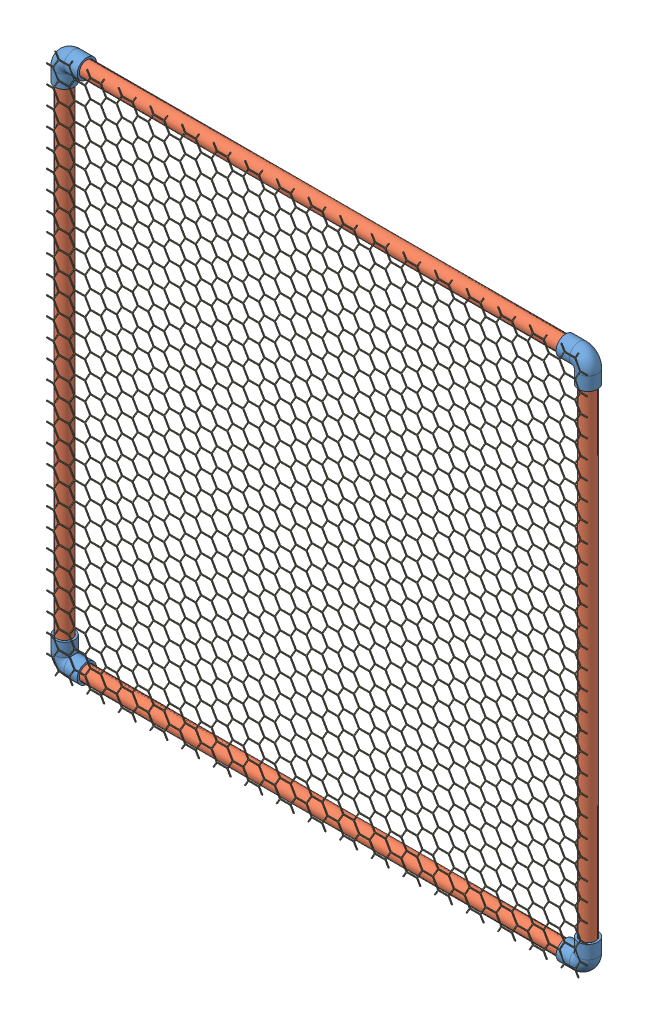
SolidWorks assembly LIFT BASKET, configuration Default. Lengths in mm.
Overall size (772.96 775.18 29.9).
9 component instances, 3 part files, 19 mates.
Components (placement in the parent):
- 1-2 PVC ELBOW-1: 1-2 PVC ELBOW [4880K21] at (72.2447 -84.4761 79.3271) size (45.53 45.53 27.56)
- 1-2 PVC ELBOW-2: 1-2 PVC ELBOW [4880K21] at (-673.1553 -84.4761 79.3271) x (0 -1 0) z (0 0 1) size (45.53 45.53 27.56)
- 1-2 PVC ELBOW-3: 1-2 PVC ELBOW [4880K21] at (-673.1553 660.9239 79.3271) x (0 1 0) z (0 0 -1) size (45.53 45.53 27.56)
- 1-2 PVC ELBOW-4: 1-2 PVC ELBOW [4880K21] at (72.2447 660.9239 79.3271) x (1 0 0) z (0 0 -1) size (45.53 45.53 27.56)
- 1-2 PVC PIPE 72CM-1: 1-2 PVC PIPE 72CM [48925K91] at (-673.1553 288.2239 79.3271) x (0.962281 0 0.272059) z (0 -1 0) size (21.34 21.34 720)
- 1-2 PVC PIPE 72CM-2: 1-2 PVC PIPE 72CM [48925K91] at (-300.4553 660.9239 79.3271) x (0 0.825172 -0.564882) z (-1 0 0) size (21.34 21.34 720)
- 1-2 PVC PIPE 72CM-3: 1-2 PVC PIPE 72CM [48925K91] at (72.2447 288.2239 79.3271) x (0.996108 0 -0.088144) z (0 1 0) size (21.34 21.34 720)
- 1-2 PVC PIPE 72CM-4: 1-2 PVC PIPE 72CM [48925K91] at (-300.4553 -84.4761 79.3271) x (0 0.606649 -0.79497) z (-1 0 0) size (21.34 21.34 720)
- MESH B-1: MESH B [Default] at (-300.4553 288.2239 93.1066) x (1 0 0) z (0 1 0) size (770 1 770)
Mates (geometry in assembly coordinates):
- Coincident1: coincident anti-aligned: plane of 1-2 PVC ELBOW-2 through (-673.1553 -71.7761 79.3271) normal (0 1 0); plane of 1-2 PVC PIPE 72CM-1 through (-673.1553 -71.7761 79.3271) normal (0 -1 0)
- Concentric1: concentric aligned: cylinder of 1-2 PVC ELBOW-2 through (-673.1553 -52.7261 79.3271) axis (0 1 0) radius 13.7795; cylinder of 1-2 PVC PIPE 72CM-1 through (-673.1553 -71.7761 79.3271) axis (0 1 0) radius 10.668
- Coincident2: coincident anti-aligned: plane of 1-2 PVC ELBOW-3 through (-673.1553 648.2239 79.3271) normal (0 -1 0); plane of 1-2 PVC PIPE 72CM-1 through (-673.1553 648.2239 79.3271) normal (0 1 0)
- Concentric2: concentric anti-aligned: cylinder of 1-2 PVC ELBOW-3 through (-673.1553 629.1739 79.3271) axis (0 -1 0) radius 13.7795; cylinder of 1-2 PVC PIPE 72CM-1 through (-673.1553 -71.7761 79.3271) axis (0 1 0) radius 10.668
- Coincident3: coincident anti-aligned: plane of 1-2 PVC ELBOW-3 through (-660.4553 660.9239 79.3271) normal (1 0 0); plane of 1-2 PVC PIPE 72CM-2 through (-660.4553 660.9239 79.3271) normal (-1 0 0)
- Concentric3: concentric anti-aligned: cone of 1-2 PVC ELBOW-3 through (-641.4053 660.9239 79.3271) axis (-1 0 0); cylinder of 1-2 PVC PIPE 72CM-2 through (-660.4553 660.9239 79.3271) axis (1 0 0) radius 10.668
- Coincident4: coincident anti-aligned: plane of 1-2 PVC ELBOW-4 through (59.5447 660.9239 79.3271) normal (-1 0 0); plane of 1-2 PVC PIPE 72CM-2 through (59.5447 660.9239 79.3271) normal (1 0 0)
- Concentric4: concentric anti-aligned: cylinder of 1-2 PVC ELBOW-4 through (40.4947 660.9239 79.3271) axis (-1 0 0) radius 13.7795; cylinder of 1-2 PVC PIPE 72CM-2 through (-660.4553 660.9239 79.3271) axis (1 0 0) radius 10.668
- Coincident5: coincident anti-aligned: plane of 1-2 PVC ELBOW-4 through (72.2447 648.2239 79.3271) normal (0 -1 0); plane of 1-2 PVC PIPE 72CM-3 through (72.2447 648.2239 79.3271) normal (0 1 0)
- Concentric5: concentric anti-aligned: cone of 1-2 PVC ELBOW-4 through (72.2447 629.1739 79.3271) axis (0 1 0); cylinder of 1-2 PVC PIPE 72CM-3 through (72.2447 648.2239 79.3271) axis (0 -1 0) radius 10.668
- Coincident6: coincident anti-aligned: plane of 1-2 PVC ELBOW-1 through (72.2447 -71.7761 79.3271) normal (0 1 0); plane of 1-2 PVC PIPE 72CM-3 through (72.2447 -71.7761 79.3271) normal (0 -1 0)
- Concentric6: concentric aligned: cylinder of 1-2 PVC ELBOW-1 through (72.2447 -84.4761 79.3271) axis (0 -1 0) radius 13.7795; cylinder of 1-2 PVC PIPE 72CM-3 through (72.2447 648.2239 79.3271) axis (0 -1 0) radius 10.668
- Concentric7: concentric anti-aligned: cylinder of 1-2 PVC ELBOW-1 through (40.4947 -84.4761 79.3271) axis (-1 0 0) radius 13.7795; cylinder of 1-2 PVC PIPE 72CM-4 through (-660.4553 -84.4761 79.3271) axis (1 0 0) radius 10.668
- Coincident7: coincident anti-aligned: plane of 1-2 PVC ELBOW-1 through (59.5447 -84.4761 79.3271) normal (-1 0 0); plane of 1-2 PVC PIPE 72CM-4 through (59.5447 -84.4761 79.3271) normal (1 0 0)
- Concentric8: concentric anti-aligned: cone of 1-2 PVC ELBOW-2 through (-641.4053 -84.4761 79.3271) axis (-1 0 0); cylinder of 1-2 PVC PIPE 72CM-4 through (-660.4553 -84.4761 79.3271) axis (1 0 0) radius 10.668
- Tangent1: tangent aligned: cylinder of 1-2 PVC ELBOW-1 through (72.2447 -84.4761 79.3271) axis (0 -1 0) radius 13.7795; plane of MESH B-1 through (-300.4553 288.2239 93.1066) normal (0 0 1)
- Parallel1: parallel anti-aligned: plane of MESH B-1 through (-300.4553 288.2239 93.1066) normal (0 0 -1); plane of assembly
- Coincident9: coincident anti-aligned: plane of 1-2 PVC PIPE 72CM-1 through (-673.1553 288.2239 79.3271) normal (0 -1 0); plane of MESH B-1 through (-300.4553 288.2239 93.1066) normal (0 1 0)
- Coincident10: coincident anti-aligned: plane of 1-2 PVC PIPE 72CM-2 through (-300.4553 660.9239 79.3271) normal (-1 0 0); plane of MESH B-1
